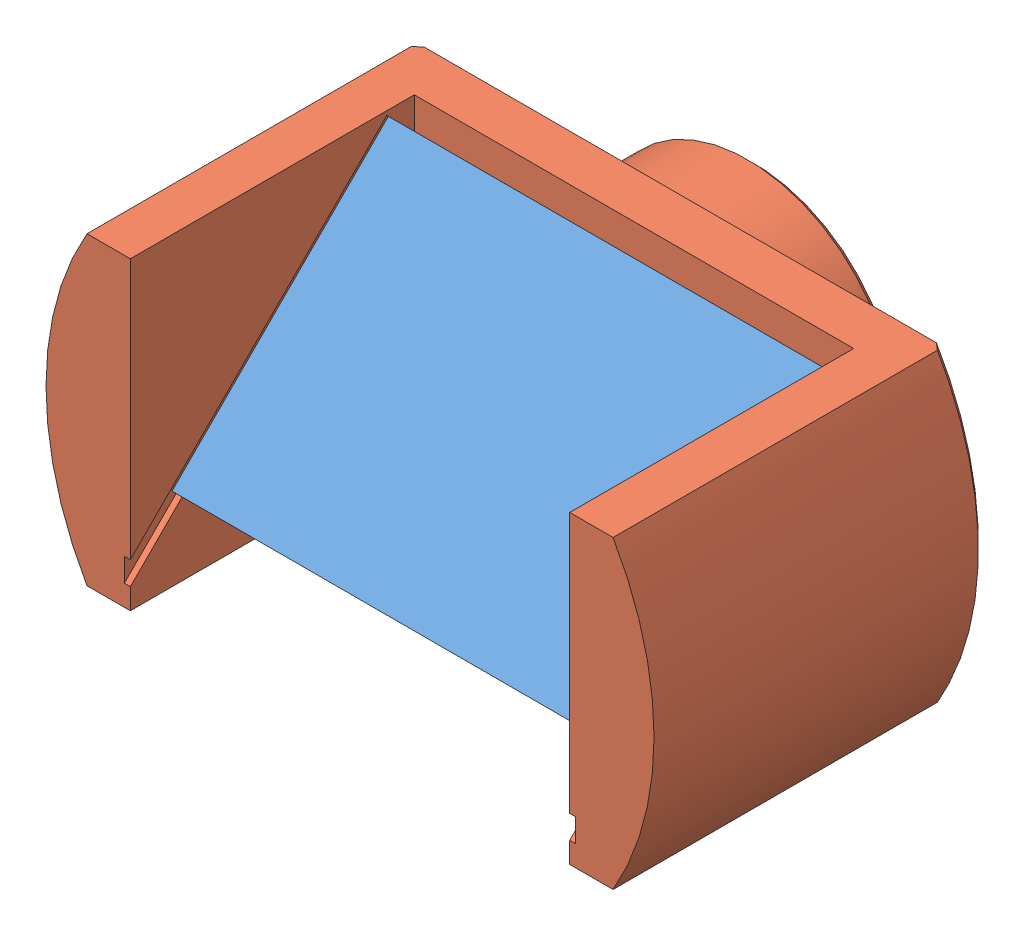
SolidWorks assembly LenseFixture3, configuration Default. Lengths in mm.
Overall size (51.67 25.91 34.29).
2 component instances, 2 part files, 3 mates.
Components (placement in the parent):
- Lense1-1: Lense1 [Default] at (-33.1938 32.3169 6.4632) x (-1 0 0) z (0 0.707107 0.707107) size (38 26 1)
- Newport-UPA-CH1_4-1: Newport-UPA-CH1_4 [預設] at (-67.2353 20.7064 -5.0403) size (51.67 25.91 34.29)
Mates (geometry in assembly coordinates):
- Coincident1: coincident: plane of Lense1-1 through (-33.1938 33.024 7.1704) normal (0 0.707107 -0.707107); plane of Newport-UPA-CH1_4-1 through (-71.5478 20.7599 -5.0938) normal (0 -0.707107 0.707107)
- Coincident2: coincident: plane of Lense1-1 through (-33.1938 32.3169 6.4632) normal (0 -0.707107 -0.707107); plane of Newport-UPA-CH1_4-1 through (-71.5478 32.2634 6.5167) normal (0 0.707107 0.707107)
- Coincident3: coincident anti-aligned: plane of Lense1-1 through (-33.1938 33.024 7.1704) normal (1 0 0); plane of Newport-UPA-CH1_4-1 through (-33.1938 20.7064 -5.0403) normal (-1 0 0)
